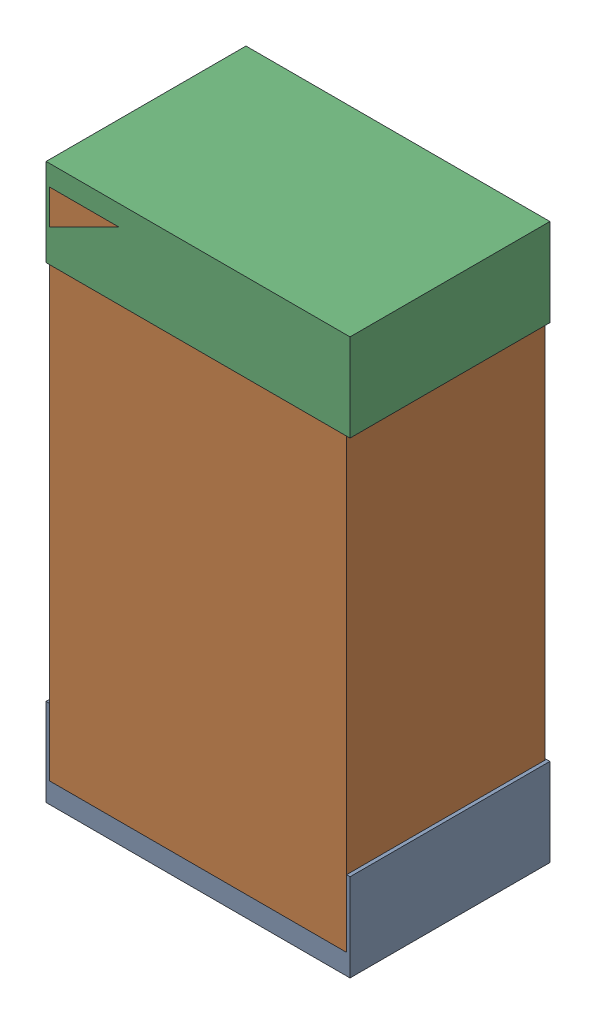
SolidWorks assembly R14Kanaloa_v2.0.0_Motor, configuration Default. Lengths in mm.
Overall size (1.3 2.38 0.85).
6 component instances, 2 part files, 0 mates.
Components (placement in the parent):
- 330415056-1: 330415056 [Default] at (87.376 70.628 -1.9574) size (1.3 0.38 0.85)
  - Extruded_2-1: Extruded_2 [Default] at origin size (1.3 0.38 0.85)
- 334787376-1: 334787376 [Default] at (87.376 71.628 -1.9524) size (1.27 2.2 0.85)
  - Extruded_16-1: Extruded_16 [Default] at origin size (1.27 2.2 0.85)
- 330415056-2: 330415056 [Default] at (87.376 72.628 -1.9574) size (1.3 0.38 0.85)
  - Extruded_2-1: Extruded_2 [Default] at origin size (1.3 0.38 0.85)
